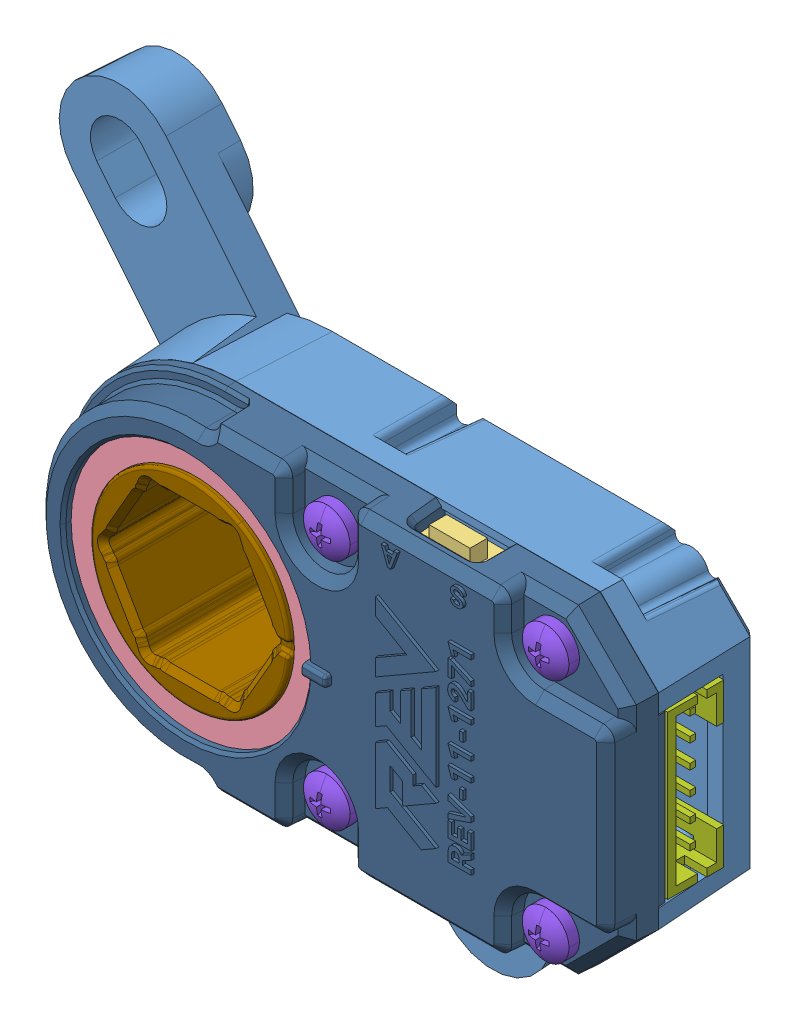
SolidWorks assembly REV-11-1271, configuration Default. Lengths in mm.
Overall size (57.37 49.78 15.83).
15 component instances, 10 part files, 0 mates.
Components (placement in the parent):
- REV-11-1271.STEP-1: REV-11-1271.STEP [Default] at origin size (57.37 49.78 15.83)
  - REV-11-1271-1.STEP-1: REV-11-1271-1.STEP [Default] at origin size (57.37 49.78 11)
  - REV-11-1271-4.STEP-1: REV-11-1271-4.STEP [Default] at (19 0 6.75) x (0.608151 -0.793821 0) z (0 0 -1) size (20 19.96 6.5)
  - REV-11-1271-0.STEP-1: REV-11-1271-0.STEP [Default] at (19 0 9.83) x (1 0 0) z (0 0 -1) size (25.5 26 4.1)
  - 6703-ZZ Bearing.STEP-1: 6703-ZZ Bearing.STEP [Default] at (0 0 1) x (0.998762 0.049742 0) z (0 0 1) size (23 23 4)
  - 128-2Z Bearing_7804K145.STEP-1: 128-2Z Bearing_7804K145.STEP [Default] at (19 0 3.35) x (-0.923728 -0.383049 0) z (0 0 -1) size (13.6 13.6 3.5)
  - REV-11-1271-5.STEP-1: REV-11-1271-5.STEP [Default] at (19 0 4.2) x (0.131669 0.991294 0) z (0.991294 -0.131669 0) size (6 2.5 6)
  - S6B-PH-K-S.STEP-1: S6B-PH-K-S.STEP [Default] at (23.264 -11.75 2.23) x (0 -1 0) z (1 0 0) size (13.9 8.2 7.6)
  - cross recessed thread forming screws gb_GB_CROSS_SCREWS_TYPE138 M2X8X7.2-N.STEP-1: cross recessed thread forming screws gb_GB_CROSS_SCREWS_TYPE138 M2X8X7.2-N.STEP [Default] at (30 -10.5 13.18) x (0 0 -1) z (1 0 0) size (9.59 4 4)
  - cross recessed thread forming screws gb_GB_CROSS_SCREWS_TYPE138 M2X8X7.2-N.STEP-2: cross recessed thread forming screws gb_GB_CROSS_SCREWS_TYPE138 M2X8X7.2-N.STEP [Default] at (30 10.5 13.18) x (0 0 -1) z (1 0 0) size (9.59 4 4)
  - cross recessed thread forming screws gb_GB_CROSS_SCREWS_TYPE138 M2X8X7.2-N.STEP-3: cross recessed thread forming screws gb_GB_CROSS_SCREWS_TYPE138 M2X8X7.2-N.STEP [Default] at (11.25 10 13.18) x (0 0 -1) z (1 0 0) size (9.59 4 4)
  - cross recessed thread forming screws gb_GB_CROSS_SCREWS_TYPE138 M2X8X7.2-N.STEP-4: cross recessed thread forming screws gb_GB_CROSS_SCREWS_TYPE138 M2X8X7.2-N.STEP [Default] at (11.25 -10 13.18) x (0 0 -1) z (1 0 0) size (9.59 4 4)
  - REV-11-1271-3 Alt.STEP-1: REV-11-1271-3 Alt.STEP [Default] at (0 0 5.5) x (-0.499334 -0.86641 0) z (0 0 1) size (20 19.96 12.5)
  - 6703-ZZ Bearing.STEP-2: 6703-ZZ Bearing.STEP [Default] at (0 0 8.5) size (23 23 4)
  - REV-11-1271-2 ALT.STEP-1: REV-11-1271-2 ALT.STEP [Default] at (36.214 13.786 12.33) x (1 0 0) z (0 0 -1) size (50 27.57 5.4)
